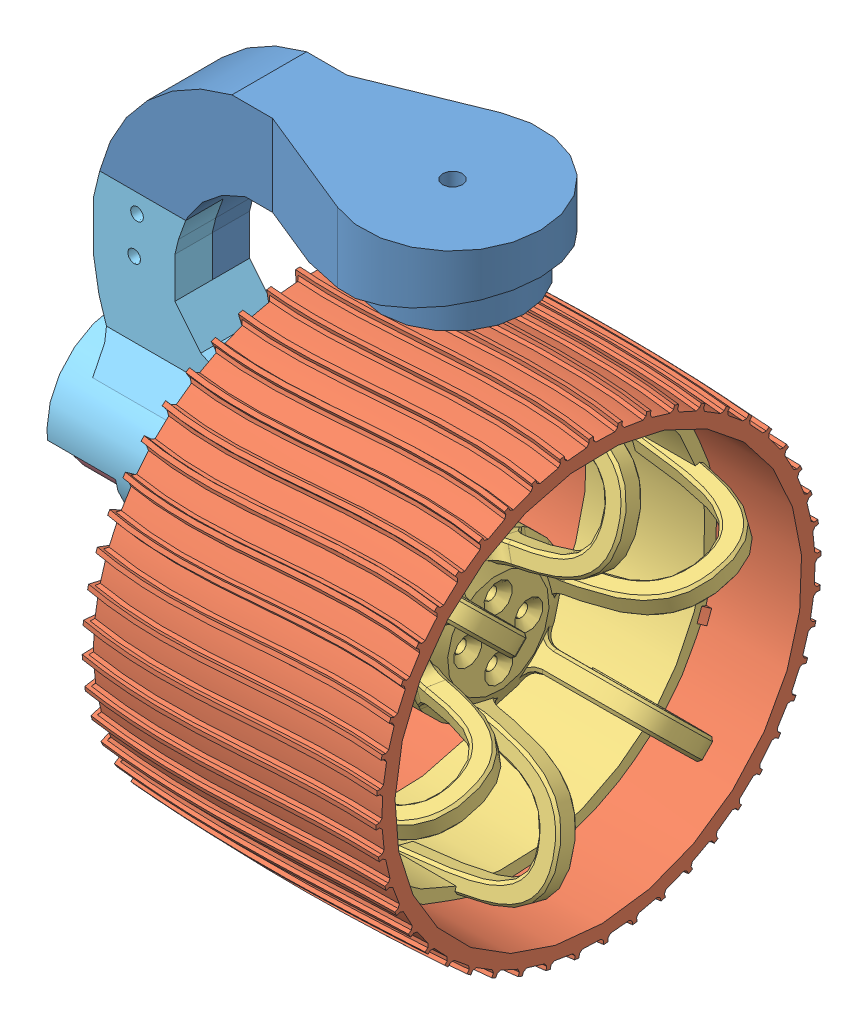
SolidWorks assembly Steering Wheel Assembly, configuration Default. Lengths in mm.
Overall size (144.76 193.85 169.7).
6 component instances, 6 part files, 13 mates.
Components (placement in the parent):
- Wheel 1 Joint-1: Wheel 1 Joint [Default] at (0 -43.7591 0) size (120.79 61.08 52)
- Wheel v.1-1: Wheel v.1 [Default] at (0.5 -128.7591 0) x (1 0 0) z (0 -0.995261 0.097238) size (86.61 139.24 139.24)
- Rim-1: Rim [Default] at (-7 -128.7591 0) x (0 0.699862 0.714278) z (1 0 0) size (120 120 60.26)
- DC Motor 12V - XD-37G555-1: DC Motor 12V - XD-37G555 [Default] at (-15 -121.7591 0) x (0 0 -1) z (-1 0 0) size (37 37 107)
- Wheel 1 Joint p2-1: Wheel 1 Joint p2 [Default] at (0 -43.7591 0) size (88 84.63 43)
- Rim and DC Motor Coupler-1: Rim and DC Motor Coupler [Default] at (-7.5 -128.7591 0) x (0 -0.699862 -0.714278) z (1 0 0) size (29.95 29.95 13)
Mates (geometry in assembly coordinates):
- Concentric408: concentric anti-aligned: cylinder of Wheel 1 Joint-1 through (-81.9602 -64.1287 -26) axis (0 0 1) radius 1.9; cylinder of Wheel 1 Joint p2-1 through (-81.9602 -64.1287 21.5) axis (0 0 -1) radius 1.9
- Concentric409: concentric anti-aligned: cylinder of Wheel 1 Joint-1 through (-82.7865 -75.3344 -26) axis (0 0 1) radius 1.9; cylinder of Wheel 1 Joint p2-1 through (-82.7865 -75.3344 21.5) axis (0 0 -1) radius 1.9
- Coincident92: coincident anti-aligned: plane of Wheel 1 Joint-1 through (26.001 -58.6287 0) normal (0 0 1); plane of Wheel 1 Joint p2-1 through (26.001 -58.6287 0) normal (0 0 -1)
- Concentric403: concentric anti-aligned: cylinder of Wheel v.1-1 through (0.5 -128.7591 0) axis (1 0 0) radius 60; cylinder of Rim-1 through (-7 -128.7591 0) axis (-1 0 0) radius 60
- Distance12: distance = 25 mm aligned: plane of Rim-1 through (18 -128.7591 0) normal (1 0 0); plane of Wheel v.1-1 through (43 -128.7591 0) normal (1 0 0)
- Concentric410: concentric anti-aligned: cylinder of DC Motor 12V - XD-37G555-1 through (-96 -121.7591 0) axis (1 0 0) radius 18.5; cylinder of Wheel 1 Joint p2-1 through (-15 -121.7591 0) axis (-1 0 0) radius 18.6
- Coincident94: coincident anti-aligned: plane of DC Motor 12V - XD-37G555-1 through (-15 -121.7591 0) normal (1 0 0); plane of Wheel 1 Joint p2-1 through (-15 -121.7591 0) normal (-1 0 0)
- Concentric411: concentric anti-aligned: cylinder of DC Motor 12V - XD-37G555-1 through (-9 -128.7591 0) axis (-1 0 0) radius 6; cylinder of Wheel 1 Joint p2-1 through (-98.001 -128.7591 0) axis (1 0 0) radius 6.1
- Concentric412: concentric aligned: cylinder of DC Motor 12V - XD-37G555-1 through (-6.5 -128.7591 0) axis (-1 0 0) radius 3; cylinder of Rim and DC Motor Coupler-1 through (5.5 -128.7591 0) axis (-1 0 0) radius 2.975
- Concentric413: concentric aligned: cylinder of Rim-1 through (9.5 -128.7591 0) axis (-1 0 0) radius 22.5; cylinder of Rim and DC Motor Coupler-1 through (5.5 -128.7591 0) axis (-1 0 0) radius 14.975
- Coincident96: coincident anti-aligned: plane of Rim-1 through (5.5 -128.7591 0) normal (-1 0 0); plane of Rim and DC Motor Coupler-1 through (5.5 -128.7591 0) normal (1 0 0)
- Concentric414: concentric anti-aligned: cylinder of Rim-1 through (13.5 -128.6674 -8.9995) axis (1 0 0) radius 1.9; cylinder of Rim and DC Motor Coupler-1 through (5.5 -128.6674 -8.9995) axis (-1 0 0) radius 2
- Coincident97: coincident anti-aligned: plane of Rim-1 through (5.5 -128.7591 0) normal (-1 0 0); plane of DC Motor 12V - XD-37G555-1 through (5.5 -121.7591 0) normal (1 0 0)
